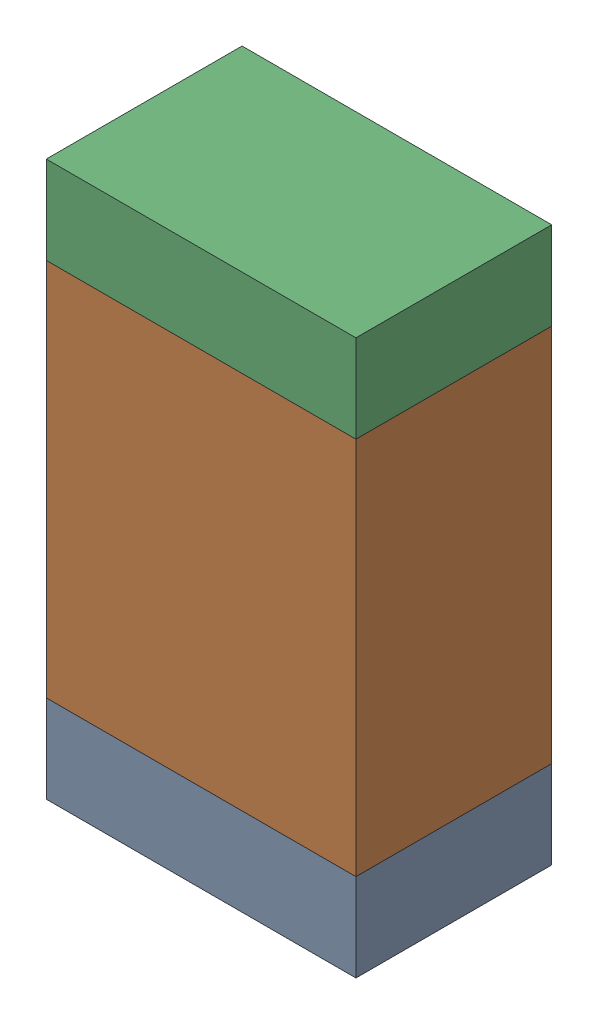
SolidWorks assembly R05, configuration Default. Lengths in mm.
Overall size (0.95 1.7 0.6).
6 component instances, 2 part files, 0 mates.
Components (placement in the parent):
- 959206216-1: 959206216 [Default] at (123.9521 73.9609 0) size (0.95 0.27 0.6)
  - Extruded-1: Extruded [Default] at origin size (0.95 0.27 0.6)
- 959206352-1: 959206352 [Default] at (123.9521 74.6759 0) size (0.95 1.16 0.6)
  - Extruded-1-1: Extruded-1 [Default] at origin size (0.95 1.16 0.6)
- 959206216-2: 959206216 [Default] at (123.9521 75.3909 0) size (0.95 0.27 0.6)
  - Extruded-1: Extruded [Default] at origin size (0.95 0.27 0.6)
